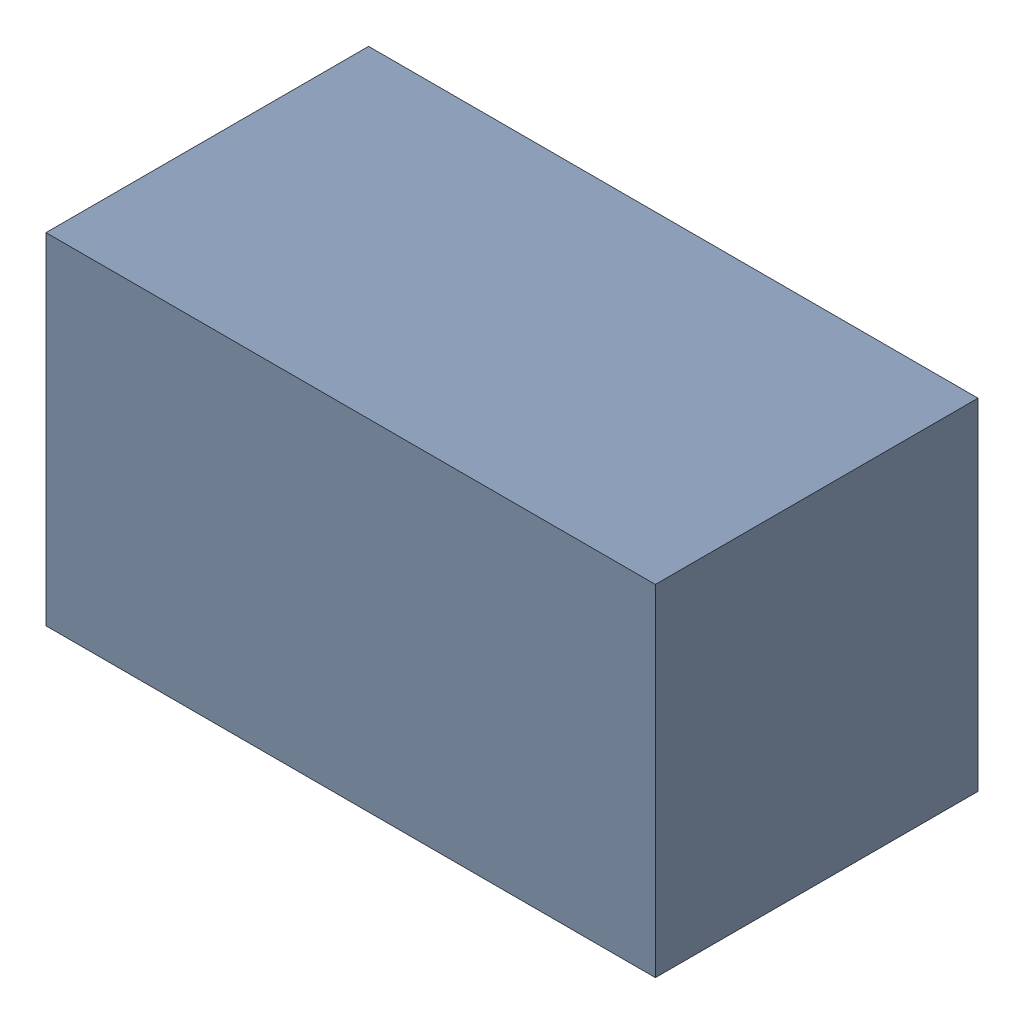
SolidWorks assembly R4_1, configuration Default. Lengths in mm.
Overall size (1.7 0.95 0.9).
2 component instances, 1 part files, 0 mates.
Components (placement in the parent):
- 5808184896-1: 5808184896 [Default] at (18.046 12.827 0) size (1.7 0.95 0.9)
  - Extruded_1_3-1: Extruded_1_3 [Default] at origin size (1.7 0.95 0.9)
